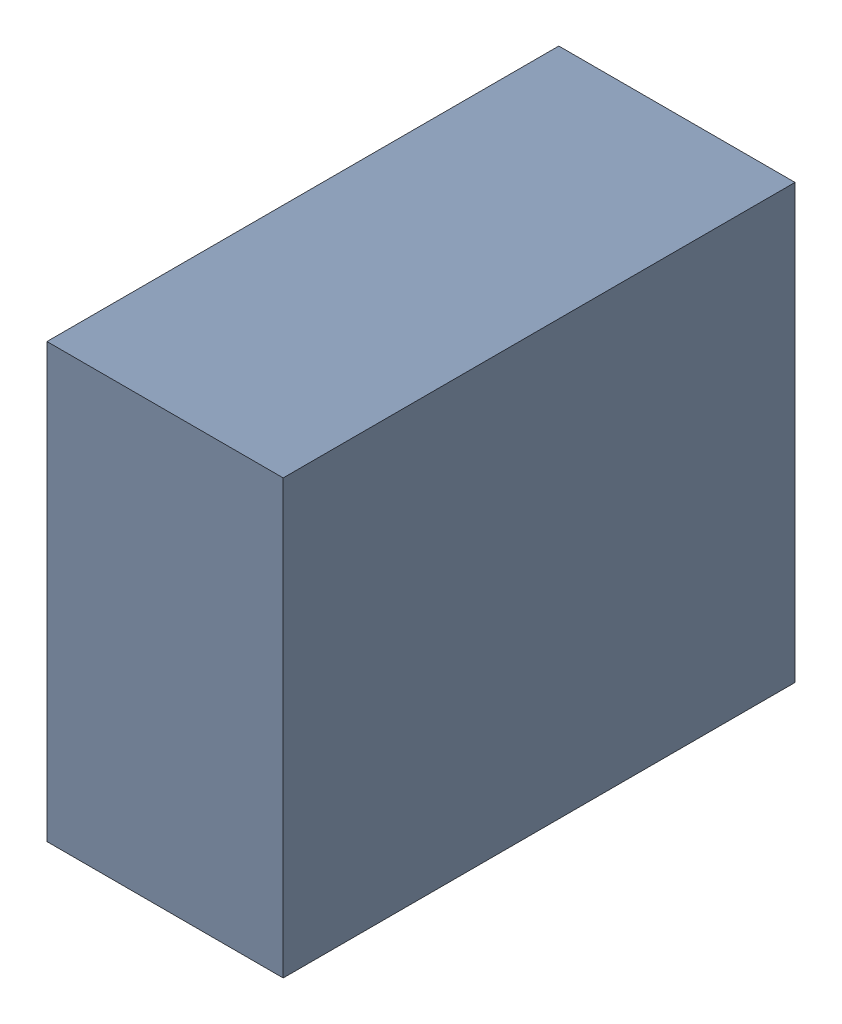
SolidWorks assembly C31_TDA4, configuration Standard. Lengths in mm.
Overall size (0.6 1.1 1.3).
2 component instances, 1 part files, 0 mates.
Components (placement in the parent):
- 885542376-1: 885542376 [Standard] at (0.91 -60.71 0) size (0.6 1.1 1.3)
  - Extruded_25-1: Extruded_25 [Standard] at origin size (0.6 1.1 1.3)
